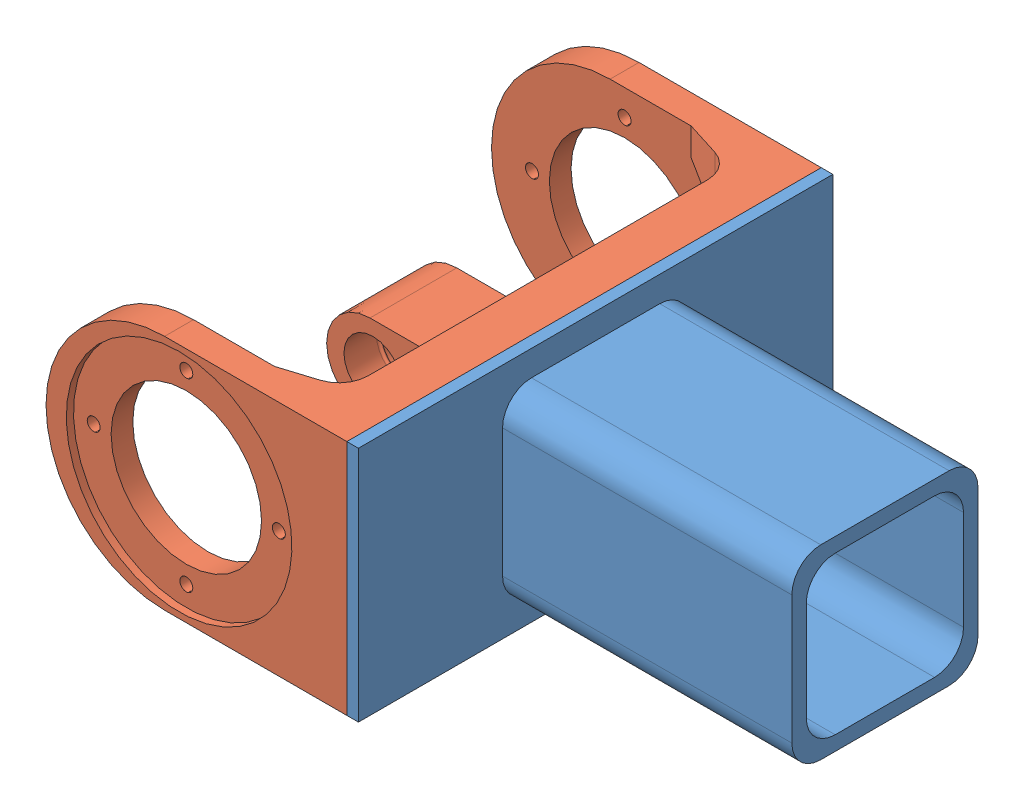
SolidWorks assembly Wrist input frame_combined, configuration Default. Lengths in mm.
Overall size (208 82 164).
2 component instances, 2 part files, 3 mates.
Components (placement in the parent):
- Wrist mount-1: Wrist mount [Default] at (-20.5195 112.5132 121.1695) size (104 82 164)
- Wrist input frame-1: Wrist input frame [Default] at (-20.5195 153.5132 121.1695) x (0 0 -1) z (0 1 0) size (164 104 82)
Mates (geometry in assembly coordinates):
- Distance1: distance = 0 mm anti-aligned: plane of Wrist input frame-1 through (-20.5195 71.5132 121.1695) normal (1 0 0); plane of Wrist mount-1 through (-20.5195 112.5132 121.1695) normal (-1 0 0)
- Distance2: distance = 0 mm aligned: plane of Wrist input frame-1 through (-20.5195 153.5132 121.1695) normal (0 1 0); plane of Wrist mount-1 through (-16.5195 153.5132 203.1695) normal (0 1 0)
- Distance3: distance = 0 mm aligned: plane of Wrist mount-1 through (-16.5195 71.5132 203.1695) normal (0 0 1); plane of Wrist input frame-1 through (-20.5195 71.5132 203.1695) normal (0 0 1)
